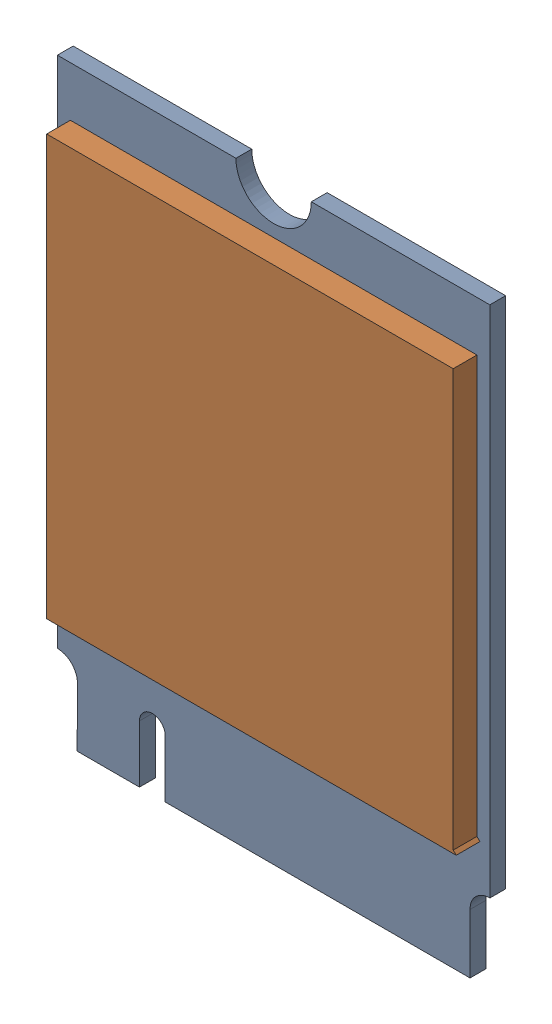
SolidWorks assembly m.2 SSD 2230, configuration Défaut. Lengths in mm.
Overall size (21.86 29.97 2).
5 component instances, 2 part files, 0 mates.
Components (placement in the parent):
- Board_1174-1: Board_1174 [Défaut] at origin size (21.86 29.97 0.8)
  - Open CASCADE STEP translator 7.5 3.1.1-1: Open CASCADE STEP translator 7.5 3.1.1 [Défaut] at (0 0 -0.8) size (21.86 29.97 0.8)
- Free-Models-1: Free-Models [Défaut] at origin size (20.72 21.22 1.2)
  - 13909094304-1: 13909094304 [Défaut] at (51.6338 57.7291 0) size (20.72 21.22 1.2)
    - Extruded_1180-1: Extruded_1180 [Défaut] at origin size (20.72 21.22 1.2)
